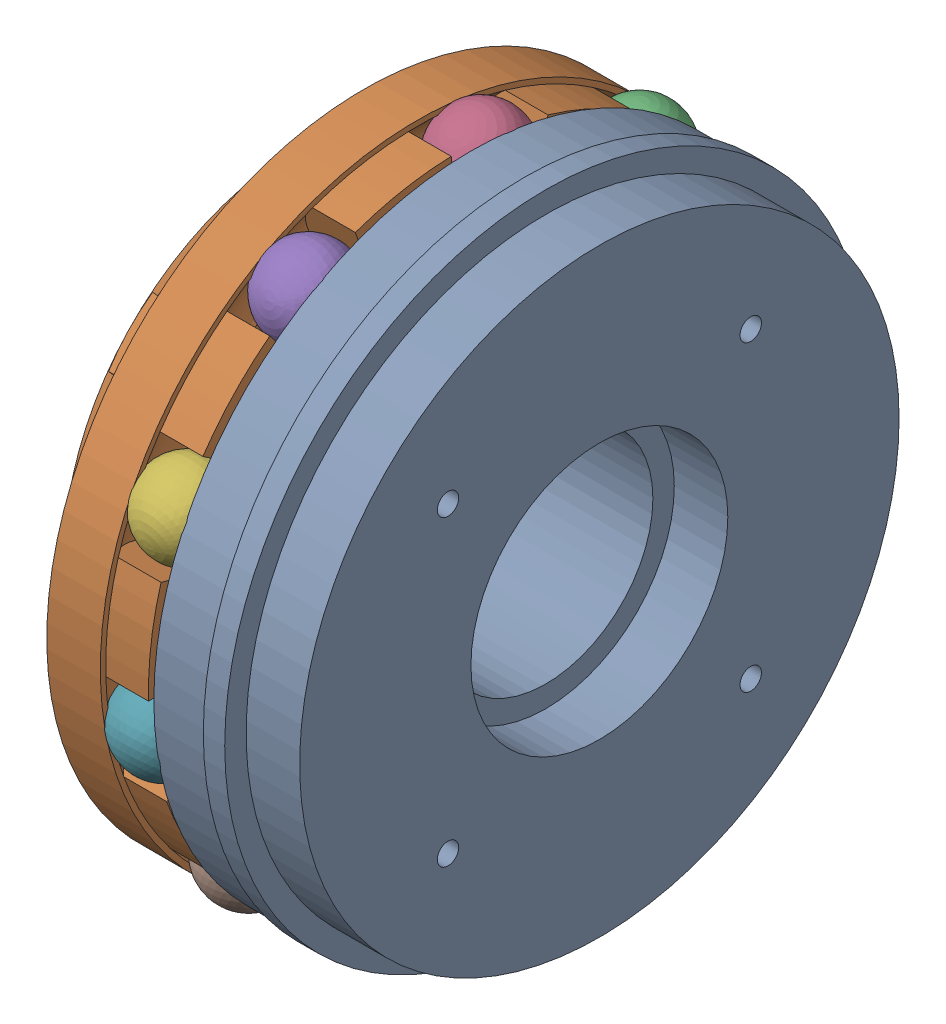
SolidWorks assembly 02-008, configuration 默认. Lengths in mm.
Overall size (28 83.75 83.75).
12 component instances, 3 part files, 0 mates.
Components (placement in the parent):
- 01-032-1: 01-032 [默认] at origin size (28 60 60)
- 01-033-1: 01-033 [默认] at (10 0 0) x (1 0 0) z (0 -0.727179 0.686448) size (15 59.24 59.24)
- 01-034-1: 01-034 [默认] at (13.5 19.2934 -18.2556) size (8 8 8)
- 01-034-2: 01-034 [默认] at (13.5 26.339 -3.4287) x (1 0 0) z (0 -0.587785 0.809017) size (8 8 8)
- 01-034-3: 01-034 [默认] at (13.5 23.324 12.7078) x (1 0 0) z (0 -0.951057 0.309017) size (8 8 8)
- 01-034-4: 01-034 [默认] at (13.5 11.4001 23.9904) x (1 0 0) z (0 -0.951057 -0.309017) size (8 8 8)
- 01-034-5: 01-034 [默认] at (13.5 -4.8783 26.1094) x (1 0 0) z (0 -0.587785 -0.809017) size (8 8 8)
- 01-034-6: 01-034 [默认] at (13.5 -19.2934 18.2556) x (1 0 0) z (0 0 -1) size (8 8 8)
- 01-034-7: 01-034 [默认] at (13.5 -26.339 3.4287) x (1 0 0) z (0 0.587785 -0.809017) size (8 8 8)
- 01-034-8: 01-034 [默认] at (13.5 -23.324 -12.7078) x (1 0 0) z (0 0.951057 -0.309017) size (8 8 8)
- 01-034-9: 01-034 [默认] at (13.5 -11.4001 -23.9904) x (1 0 0) z (0 0.951057 0.309017) size (8 8 8)
- 01-034-10: 01-034 [默认] at (13.5 4.8783 -26.1094) x (1 0 0) z (0 0.587785 0.809017) size (8 8 8)
